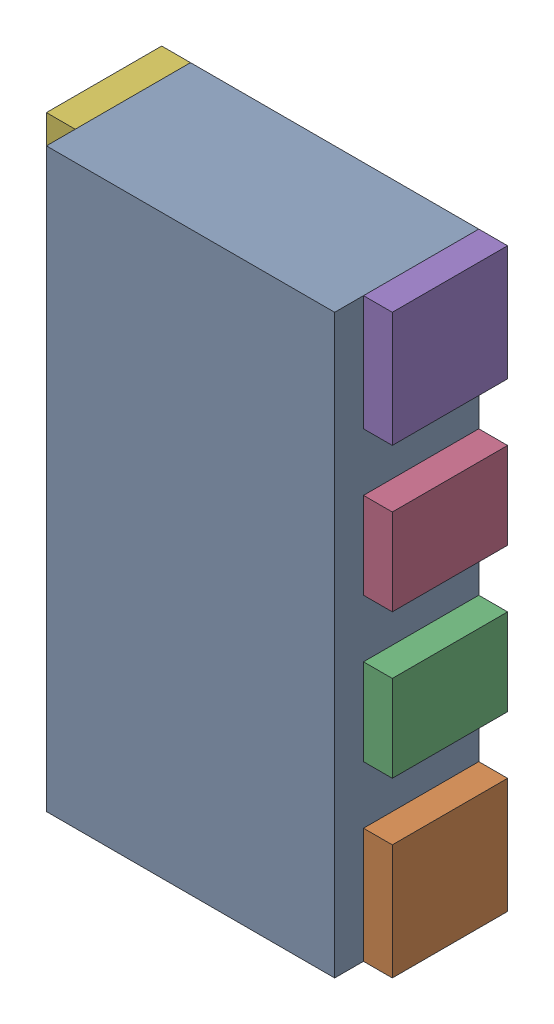
SolidWorks assembly RN6, configuration Default. Lengths in mm.
Overall size (1.2 2 0.5).
18 component instances, 3 part files, 0 mates.
Components (placement in the parent):
- 836750320-1: 836750320 [Default] at (107.05 32.95 0) size (1 2 0.5)
  - Extruded_15-1: Extruded_15 [Default] at origin size (1 2 0.5)
- 791587232-1: 791587232 [Default] at (107.6 32.15 0) size (0.1 0.4 0.4)
  - Extruded_10-1: Extruded_10 [Default] at origin size (0.1 0.4 0.4)
- 836750576-1: 836750576 [Default] at (107.6 32.7 0) size (0.1 0.3 0.4)
  - Extruded_14-1: Extruded_14 [Default] at origin size (0.1 0.3 0.4)
- 836750576-2: 836750576 [Default] at (107.6 33.2 0) size (0.1 0.3 0.4)
  - Extruded_14-1: Extruded_14 [Default] at origin size (0.1 0.3 0.4)
- 791587232-2: 791587232 [Default] at (107.6 33.75 0) size (0.1 0.4 0.4)
  - Extruded_10-1: Extruded_10 [Default] at origin size (0.1 0.4 0.4)
- 791587232-3: 791587232 [Default] at (106.5 33.75 0) size (0.1 0.4 0.4)
  - Extruded_10-1: Extruded_10 [Default] at origin size (0.1 0.4 0.4)
- 836750576-3: 836750576 [Default] at (106.5 33.2 0) size (0.1 0.3 0.4)
  - Extruded_14-1: Extruded_14 [Default] at origin size (0.1 0.3 0.4)
- 836750576-4: 836750576 [Default] at (106.5 32.7 0) size (0.1 0.3 0.4)
  - Extruded_14-1: Extruded_14 [Default] at origin size (0.1 0.3 0.4)
- 791587232-4: 791587232 [Default] at (106.5 32.15 0) size (0.1 0.4 0.4)
  - Extruded_10-1: Extruded_10 [Default] at origin size (0.1 0.4 0.4)
